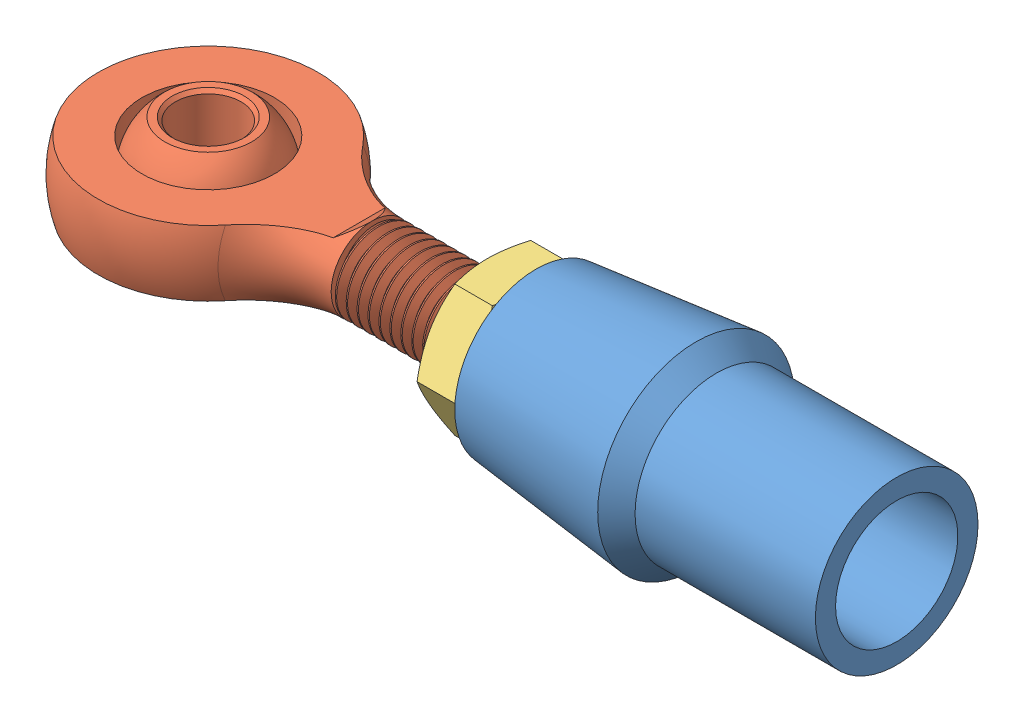
SolidWorks assembly FS2-SU-A-0002-L, LEFT HAND ROD END TUBE END ASSEMBLY, configuration Default. Lengths in mm.
Overall size (77.79 19.05 22.23).
3 component instances, 3 part files, 45 mates.
Components (placement in the parent):
- TUBE-END WELD NUT, Left Hand 0.3125-24 0.75 TUBE 0.065 WALL, 94640A114, MMC-1: TUBE-END WELD NUT, Left Hand 0.3125-24 0.75 TUBE 0.065 WALL, 94640A114, MMC [94640A114] x (0 1 0) z (0 0 1) size (19.05 35.46 19.05)
- ROD END, STEEL BALL JOINT ID 0.25 0.3125-24 Left-Hand, 60645K821, MMC-1: ROD END, STEEL BALL JOINT ID 0.25 0.3125-24 Left-Hand, 60645K821, MMC [60645K821] at (-33.3375 0 0) x (0 0 -1) z (0 1 0) size (22.23 58.96 9.53)
- THIN HEX NUT, Left Hand 0.3125-24 GRADE 5 STEEL , 99612A112, MMC-1: THIN HEX NUT, Left Hand 0.3125-24 GRADE 5 STEEL , 99612A112, MMC [99612A112] at (-19.8438 0 0) x (0 -1 0) z (0 0 1) size (12.7 5.58 14.66)
Mates (geometry in assembly coordinates):
- Coincident1: coincident anti-aligned: plane of TUBE-END WELD NUT, Left Hand 0.3125-24 0.75 TUBE 0.065 WALL, 94640A114, MMC-1 through (0 0 0) normal (-1 0 0)
- Coincident2: coincident aligned: plane of TUBE-END WELD NUT, Left Hand 0.3125-24 0.75 TUBE 0.065 WALL, 94640A114, MMC-1 through (0 0 0) normal (0 0 1)
- Coincident3: coincident aligned: plane of TUBE-END WELD NUT, Left Hand 0.3125-24 0.75 TUBE 0.065 WALL, 94640A114, MMC-1 through (0 0 0) normal (0 1 0)
- Parallel1: parallel anti-aligned: plane of ROD END, STEEL BALL JOINT ID 0.25 0.3125-24 Left-Hand, 60645K821, MMC-1 through (-60.325 -3.175 11.1125) normal (0 -1 0)
- Parallel2: parallel anti-aligned: plane of THIN HEX NUT, Left Hand 0.3125-24 GRADE 5 STEEL , 99612A112, MMC-1 through (-17.4625 -6.35 3.6662) normal (0 -1 0)
- Coincident9: coincident anti-aligned: plane of TUBE-END WELD NUT, Left Hand 0.3125-24 0.75 TUBE 0.065 WALL, 94640A114, MMC-1 through (-17.4625 -3.9688 0) normal (-1 0 0); plane of THIN HEX NUT, Left Hand 0.3125-24 GRADE 5 STEEL , 99612A112, MMC-1 through (-17.4625 6.35 -3.6662) normal (1 0 0)
- Coincident11: coincident: point of THIN HEX NUT, Left Hand 0.3125-24 GRADE 5 STEEL , 99612A112, MMC-1
- Distance1: distance = 11.1125 mm anti-aligned: plane of ROD END, STEEL BALL JOINT ID 0.25 0.3125-24 Left-Hand, 60645K821, MMC-1 through (-33.3375 0 -3.9688) normal (1 0 0); plane of THIN HEX NUT, Left Hand 0.3125-24 GRADE 5 STEEL , 99612A112, MMC-1 through (-22.225 6.35 -3.6662) normal (-1 0 0)
- Coincident12: coincident anti-aligned: line of ROD END, STEEL BALL JOINT ID 0.25 0.3125-24 Left-Hand, 60645K821, MMC-1 through (0 55.3116 -55.2694) axis (0 0 1)
- Coincident13: coincident anti-aligned: plane of TUBE-END WELD NUT, Left Hand 0.3125-24 0.75 TUBE 0.065 WALL, 94640A114, MMC-1 through (0 0 0) normal (-1 0 0)
- Coincident14: coincident aligned: plane of TUBE-END WELD NUT, Left Hand 0.3125-24 0.75 TUBE 0.065 WALL, 94640A114, MMC-1 through (0 0 0) normal (0 0 1)
- Coincident15: coincident aligned: plane of TUBE-END WELD NUT, Left Hand 0.3125-24 0.75 TUBE 0.065 WALL, 94640A114, MMC-1 through (0 0 0) normal (0 1 0)
- Parallel3: parallel anti-aligned: plane of ROD END, STEEL BALL JOINT ID 0.25 0.3125-24 Left-Hand, 60645K821, MMC-1 through (-60.325 -3.175 -11.1125) normal (0 -1 0)
- Parallel4: parallel anti-aligned: plane of THIN HEX NUT, Left Hand 0.3125-24 GRADE 5 STEEL , 99612A112, MMC-1 through (-17.4625 -6.35 -3.6662) normal (0 -1 0)
- Coincident16: coincident anti-aligned: plane of TUBE-END WELD NUT, Left Hand 0.3125-24 0.75 TUBE 0.065 WALL, 94640A114, MMC-1 through (-17.4625 -3.9688 0) normal (-1 0 0); plane of THIN HEX NUT, Left Hand 0.3125-24 GRADE 5 STEEL , 99612A112, MMC-1 through (-17.4625 6.35 3.6662) normal (1 0 0)
- Coincident17: coincident: unknown of THIN HEX NUT, Left Hand 0.3125-24 GRADE 5 STEEL , 99612A112, MMC-1
- Distance2: distance = 11.1125 mm anti-aligned: plane of ROD END, STEEL BALL JOINT ID 0.25 0.3125-24 Left-Hand, 60645K821, MMC-1 through (-33.3375 0 3.9688) normal (1 0 0); plane of THIN HEX NUT, Left Hand 0.3125-24 GRADE 5 STEEL , 99612A112, MMC-1 through (-22.225 6.35 3.6662) normal (-1 0 0)
- Coincident18: coincident anti-aligned: line of ROD END, STEEL BALL JOINT ID 0.25 0.3125-24 Left-Hand, 60645K821, MMC-1 through (0 55.3116 -55.2694) axis (0 0 1)
- Coincident19: coincident anti-aligned: plane of TUBE-END WELD NUT, Left Hand 0.3125-24 0.75 TUBE 0.065 WALL, 94640A114, MMC-1 through (0 0 0) normal (-1 0 0)
- Coincident20: coincident aligned: plane of TUBE-END WELD NUT, Left Hand 0.3125-24 0.75 TUBE 0.065 WALL, 94640A114, MMC-1 through (0 0 0) normal (0 0 1)
- Coincident21: coincident aligned: plane of TUBE-END WELD NUT, Left Hand 0.3125-24 0.75 TUBE 0.065 WALL, 94640A114, MMC-1 through (0 0 0) normal (0 1 0)
- Parallel5: parallel anti-aligned: plane of ROD END, STEEL BALL JOINT ID 0.25 0.3125-24 Left-Hand, 60645K821, MMC-1 through (-60.325 -3.175 -11.1125) normal (0 -1 0)
- Parallel6: parallel anti-aligned: plane of THIN HEX NUT, Left Hand 0.3125-24 GRADE 5 STEEL , 99612A112, MMC-1 through (-17.4625 -6.35 -3.6662) normal (0 -1 0)
- Coincident22: coincident anti-aligned: plane of TUBE-END WELD NUT, Left Hand 0.3125-24 0.75 TUBE 0.065 WALL, 94640A114, MMC-1 through (-17.4625 -3.9688 0) normal (-1 0 0); plane of THIN HEX NUT, Left Hand 0.3125-24 GRADE 5 STEEL , 99612A112, MMC-1 through (-17.4625 6.35 3.6662) normal (1 0 0)
- Coincident23: coincident: unknown of THIN HEX NUT, Left Hand 0.3125-24 GRADE 5 STEEL , 99612A112, MMC-1
- Distance3: distance = 11.1125 mm anti-aligned: plane of ROD END, STEEL BALL JOINT ID 0.25 0.3125-24 Left-Hand, 60645K821, MMC-1 through (-33.3375 0 3.9688) normal (1 0 0); plane of THIN HEX NUT, Left Hand 0.3125-24 GRADE 5 STEEL , 99612A112, MMC-1 through (-22.225 6.35 3.6662) normal (-1 0 0)
- Coincident24: coincident anti-aligned: line of ROD END, STEEL BALL JOINT ID 0.25 0.3125-24 Left-Hand, 60645K821, MMC-1 through (0 55.3116 -55.2694) axis (0 0 1)
- Coincident25: coincident anti-aligned: plane of TUBE-END WELD NUT, Left Hand 0.3125-24 0.75 TUBE 0.065 WALL, 94640A114, MMC-1 through (0 0 0) normal (-1 0 0)
- Coincident26: coincident aligned: plane of TUBE-END WELD NUT, Left Hand 0.3125-24 0.75 TUBE 0.065 WALL, 94640A114, MMC-1 through (0 0 0) normal (0 0 1)
- Coincident27: coincident aligned: plane of TUBE-END WELD NUT, Left Hand 0.3125-24 0.75 TUBE 0.065 WALL, 94640A114, MMC-1 through (0 0 0) normal (0 1 0)
- Parallel7: parallel anti-aligned: plane of ROD END, STEEL BALL JOINT ID 0.25 0.3125-24 Left-Hand, 60645K821, MMC-1 through (-60.325 -3.175 -11.1125) normal (0 -1 0)
- Parallel8: parallel anti-aligned: plane of THIN HEX NUT, Left Hand 0.3125-24 GRADE 5 STEEL , 99612A112, MMC-1 through (-17.4625 -6.35 -3.6662) normal (0 -1 0)
- Coincident28: coincident anti-aligned: plane of TUBE-END WELD NUT, Left Hand 0.3125-24 0.75 TUBE 0.065 WALL, 94640A114, MMC-1 through (-17.4625 -3.9688 0) normal (-1 0 0); plane of THIN HEX NUT, Left Hand 0.3125-24 GRADE 5 STEEL , 99612A112, MMC-1 through (-17.4625 6.35 3.6662) normal (1 0 0)
- Coincident29: coincident: unknown of THIN HEX NUT, Left Hand 0.3125-24 GRADE 5 STEEL , 99612A112, MMC-1
- Distance4: distance = 11.1125 mm anti-aligned: plane of ROD END, STEEL BALL JOINT ID 0.25 0.3125-24 Left-Hand, 60645K821, MMC-1 through (-33.3375 0 3.9688) normal (1 0 0); plane of THIN HEX NUT, Left Hand 0.3125-24 GRADE 5 STEEL , 99612A112, MMC-1 through (-22.225 6.35 3.6662) normal (-1 0 0)
- Coincident30: coincident anti-aligned: line of ROD END, STEEL BALL JOINT ID 0.25 0.3125-24 Left-Hand, 60645K821, MMC-1 through (0 55.3116 -55.2694) axis (0 0 1)
- Coincident31: coincident anti-aligned: plane of TUBE-END WELD NUT, Left Hand 0.3125-24 0.75 TUBE 0.065 WALL, 94640A114, MMC-1 through (0 0 0) normal (-1 0 0)
- Coincident32: coincident aligned: plane of TUBE-END WELD NUT, Left Hand 0.3125-24 0.75 TUBE 0.065 WALL, 94640A114, MMC-1 through (0 0 0) normal (0 0 1)
- Coincident33: coincident aligned: plane of TUBE-END WELD NUT, Left Hand 0.3125-24 0.75 TUBE 0.065 WALL, 94640A114, MMC-1 through (0 0 0) normal (0 1 0)
- Parallel9: parallel anti-aligned: plane of ROD END, STEEL BALL JOINT ID 0.25 0.3125-24 Left-Hand, 60645K821, MMC-1 through (-60.325 -3.175 -11.1125) normal (0 -1 0)
- Parallel10: parallel anti-aligned: plane of THIN HEX NUT, Left Hand 0.3125-24 GRADE 5 STEEL , 99612A112, MMC-1 through (-17.4625 -6.35 -3.6662) normal (0 -1 0)
- Coincident34: coincident anti-aligned: plane of TUBE-END WELD NUT, Left Hand 0.3125-24 0.75 TUBE 0.065 WALL, 94640A114, MMC-1 through (-17.4625 -3.9688 0) normal (-1 0 0); plane of THIN HEX NUT, Left Hand 0.3125-24 GRADE 5 STEEL , 99612A112, MMC-1 through (-17.4625 6.35 3.6662) normal (1 0 0)
- Coincident35: coincident: unknown of THIN HEX NUT, Left Hand 0.3125-24 GRADE 5 STEEL , 99612A112, MMC-1
- Distance5: distance = 11.1125 mm anti-aligned: plane of ROD END, STEEL BALL JOINT ID 0.25 0.3125-24 Left-Hand, 60645K821, MMC-1 through (-33.3375 0 3.9688) normal (1 0 0); plane of THIN HEX NUT, Left Hand 0.3125-24 GRADE 5 STEEL , 99612A112, MMC-1 through (-22.225 6.35 3.6662) normal (-1 0 0)
- Coincident36: coincident anti-aligned: line of ROD END, STEEL BALL JOINT ID 0.25 0.3125-24 Left-Hand, 60645K821, MMC-1 through (0 55.3116 -55.2694) axis (0 0 1)
